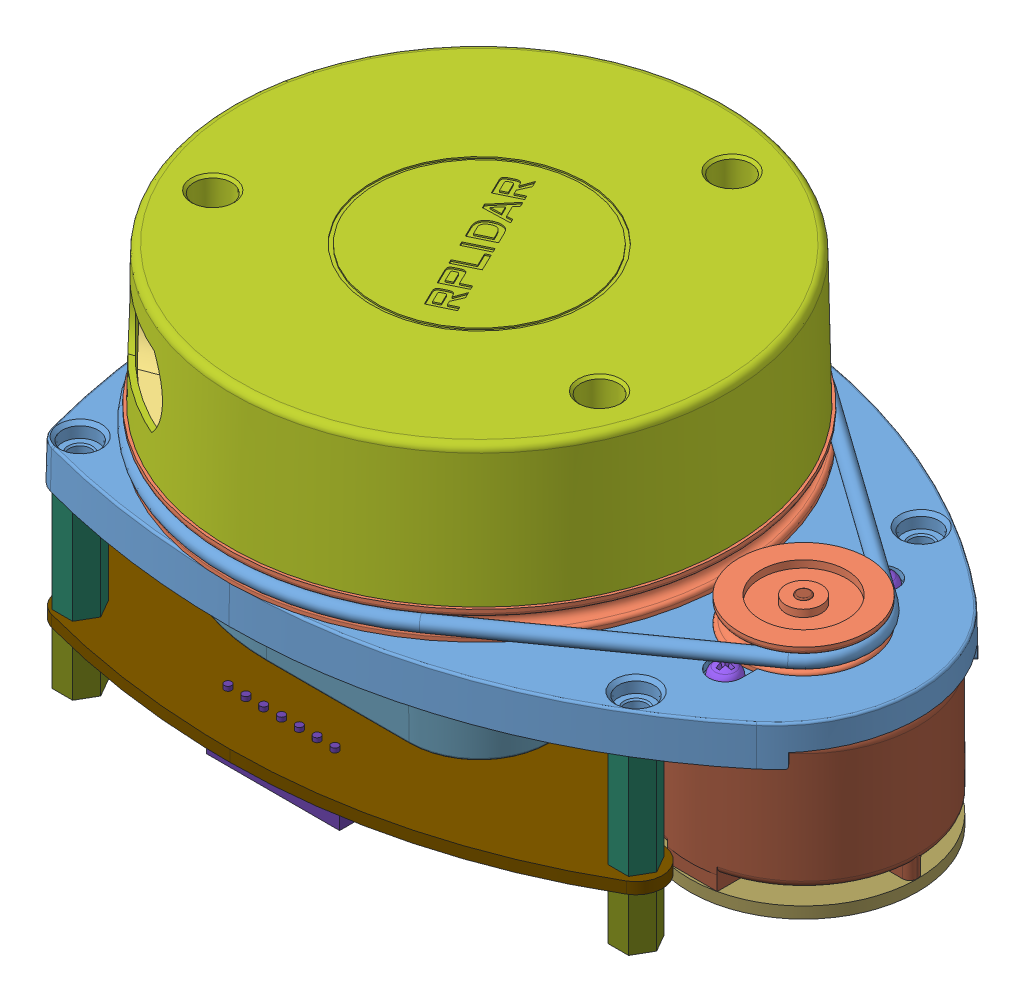
SolidWorks assembly RP-lidar-A1, configuration Défaut. Lengths in mm.
Overall size (125.66 53.5 112.5).
31 component instances, 20 part files, 0 mates.
Components (placement in the parent):
- RP-lidar-A1.igs-1: RP-lidar-A1.igs [Défaut] at origin size (125.66 53.5 112.5)
  - base.igs-1: base.igs [Défaut] at (-90.5533 748.2923 132.9176) size (107.5 12.7 70.46)
  - head-base.igs-1: head-base.igs [Défaut] at (-90.5533 751.2923 132.9176) x (0.900173 0 -0.435532) z (0.435532 0 0.900173) size (78.94 21.4 82.8)
  - detector-mount.igs-1: detector-mount.igs [Défaut] at (-90.4238 754.2923 132.7756) x (-0.437519 0 -0.899209) z (0.899209 0 -0.437519) size (22.2 19.69 24.64)
  - detector.igs-1: detector.igs [Défaut] at (-93.3269 763.2923 153.0936) x (-0.088661 0.979252 -0.182219) z (-0.899209 0 0.437519) size (14.42 15.28 11.5)
  - laser.igs-1: laser.igs [Défaut] at (-96.1268 764.2923 107.8262) x (0.382786 0.720375 0.578389) z (-0.833913 0 0.551896) size (6.5 8.25 21.2)
  - laser-mount.igs-1: laser-mount.igs [Défaut] at (-90.5533 755.2923 132.9176) x (-0.430466 0 -0.902607) z (0.902607 0 -0.430466) size (15.26 18.5 21.53)
  - head.igs-1: head.igs [Défaut] at (-90.5533 773.1923 132.9176) x (0.435532 0 0.900173) z (0.900173 0 -0.435532) size (84.91 19.5 78.26)
  - Woodscrews_GB_TYPE136 M2X6-N.igs-1: Woodscrews_GB_TYPE136 M2X6-N.igs [Défaut] at (-64.2029 766.7923 142.3864) x (0 -1 0) z (-0.876166 0 -0.482009) size (7.56 3.91 3.91)
  - Woodscrews_GB_TYPE136 M2X6-N.igs-2: Woodscrews_GB_TYPE136 M2X6-N.igs [Défaut] at (-81.6242 766.7923 106.3795) x (0 -1 0) z (-0.876166 0 -0.482009) size (7.56 3.91 3.91)
  - Woodscrews_GB_TYPE136 M2X6-N.igs-3: Woodscrews_GB_TYPE136 M2X6-N.igs [Défaut] at (-115.7581 766.7923 145.1125) x (0 -1 0) z (-0.922446 0 -0.386125) size (7.56 3.91 3.91)
  - Woodscrews_GB_TYPE136 M2X6-N.igs-4: Woodscrews_GB_TYPE136 M2X6-N.igs [Défaut] at (-45.0533 750.5923 121.9176) x (0 -1 0) z (0.032922 0 0.999458) size (7.56 3.91 3.91)
  - Woodscrews_GB_TYPE136 M2X6-N.igs-5: Woodscrews_GB_TYPE136 M2X6-N.igs [Défaut] at (-45.0533 750.5923 143.9176) x (0 -1 0) z (0.032922 0 0.999458) size (7.56 3.91 3.91)
  - motherboard.igs-1: motherboard.igs [Défaut] at (-90.5533 738.2923 132.9176) size (55.5 1 57)
  - connector-1_25-3pin.igs-1: connector-1_25-3pin.igs [Défaut] at (-57.5533 723.4923 132.5551) x (0 0 1) z (0 -1 0) size (8.9 5.2 3.4)
  - motor.igs-1: motor.igs [Défaut] at (-45.0533 728.7923 132.9176) x (0 0 1) z (-1 0 0) size (32.79 30.2 32.01)
  - motor-board.igs-1: motor-board.igs [Défaut] at (-45.0533 725.1923 132.9176) x (0.420142 0 0.907458) z (-0.907458 0 0.420142) size (32 1.6 32)
  - connector-1_25-4pin.igs-1: connector-1_25-4pin.igs [Défaut] at (-68.3533 736.4423 132.7926) x (0 0 1) z (1 0 0) size (10.15 4.2 4.7)
  - bottom-lid.igs-1: bottom-lid.igs [Défaut] at (-90.5533 737.2923 132.9176) size (61.38 11.06 61.97)
  - stand_15x2.igs-1: stand_15x2.igs [Défaut] at (-118.5533 729.2923 160.9176) size (5.77 15 5)
  - stand_15x2.igs-2: stand_15x2.igs [Défaut] at (-48.5533 729.2923 152.9176) size (5.77 15 5)
  - stand_15x2.igs-3: stand_15x2.igs [Défaut] at (-48.5533 729.2923 112.9176) size (5.77 15 5)
  - stand_15x2.igs-4: stand_15x2.igs [Défaut] at (-118.5533 729.2923 104.9176) size (5.77 15 5)
  - stand-8x2.igs-1: stand-8x2.igs [Défaut] at (-48.5533 727.6923 152.9176) x (1 0 0) z (0 0 -1) size (5.77 8 5)
  - stand-8x2.igs-2: stand-8x2.igs [Défaut] at (-118.5533 727.6923 160.9176) x (1 0 0) z (0 0 -1) size (5.77 8 5)
  - stand-8x2.igs-3: stand-8x2.igs [Défaut] at (-118.5533 727.6923 104.9176) x (1 0 0) z (0 0 -1) size (5.77 8 5)
  - stand-8x2.igs-4: stand-8x2.igs [Défaut] at (-48.5533 727.6923 112.9176) x (1 0 0) z (0 0 -1) size (5.77 8 5)
  - connector-7pin-2_5.igs-1: connector-7pin-2_5.igs [Défaut] at (-90.5533 727.6923 160.0176) x (0 -1 0) z (1 0 0) size (8.2 5 20)
  - devboard.igs-1: devboard.igs [Défaut] at (-90.5533 729.2923 132.9176) x (1 0 0) z (0 0 -1) size (85.1 7.64 70)
  - rubber.igs-1: rubber.igs [Défaut] at (-90.5533 751.4783 132.9176) x (1 0 0) z (0 -1 0) size (103.16 95.72 2.15)
  - wheel.igs-1: wheel.igs [Défaut] at (-45.0533 749.2923 132.9176) x (-0.124101 0 -0.99227) z (0.99227 0 -0.124101) size (18 5.5 18)
